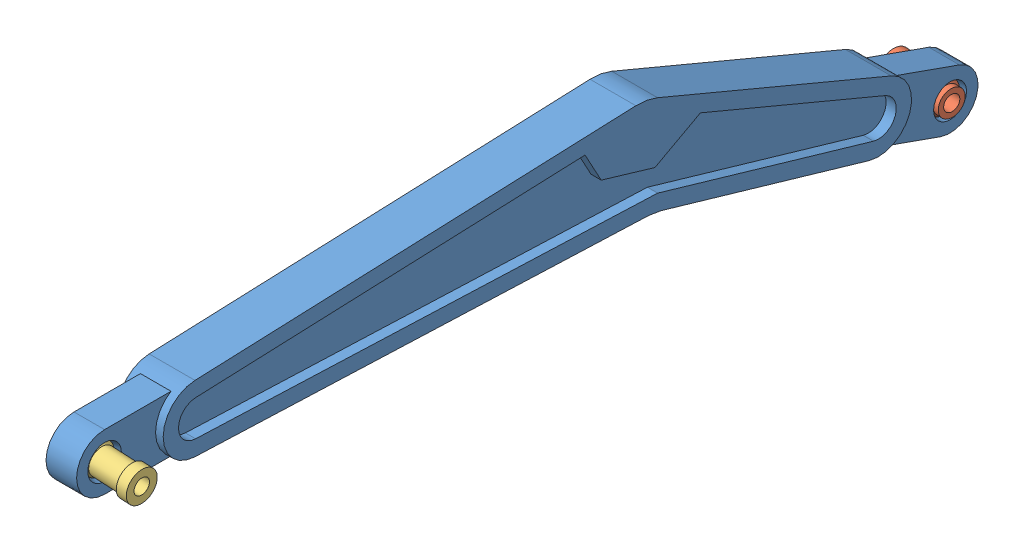
SolidWorks assembly Bar_4, configuration Default. Lengths in mm.
Overall size (19.34 37 176.95).
3 component instances, 3 part files, 2 mates.
Components (placement in the parent):
- Bar_4-1: Bar_4 [Default] at origin size (9 37 176.95)
- Ball_3-1: Ball_3 [Default] at (3.544 -21.5862 -165.7387) x (0.050825 0.562054 -0.825537) z (0.998155 -0.001103 0.060702) size (7 7 12)
- Ball_4-1: Ball_4 [Default] at (-3.5478 0.1297 -0.0484) x (-0.013025 0.016759 0.999775) z (-0.99924 0.036517 -0.01363) size (7 7 14)
Mates (geometry in assembly coordinates):
- Concentric1: concentric: sphere of Bar_4-1; sphere of Ball_4-1
- Concentric2: concentric: sphere of Bar_4-1; sphere of Ball_3-1
